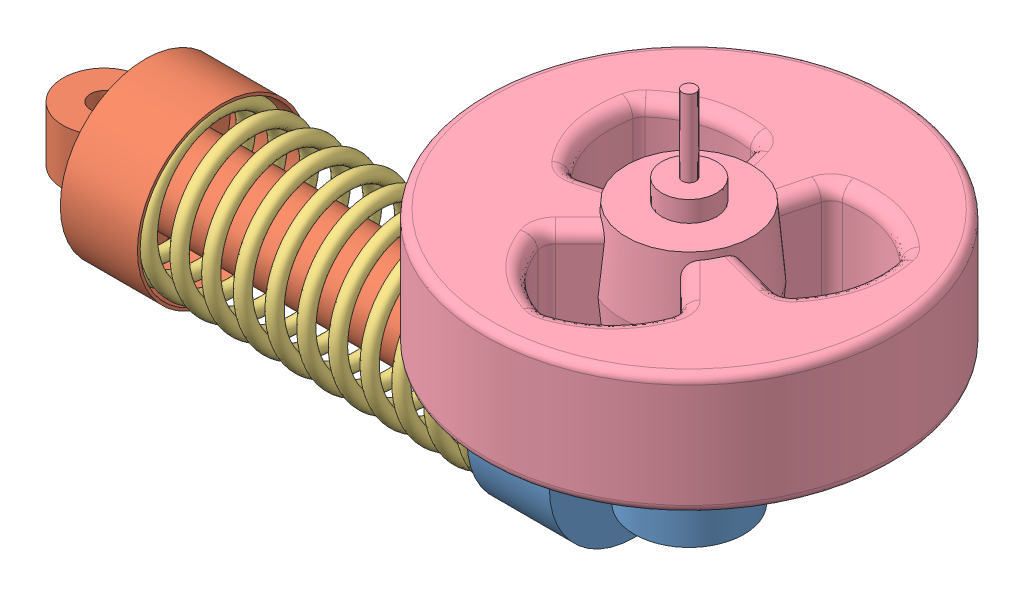
SolidWorks assembly suspension systim and tyre, configuration Default. Lengths in mm.
Overall size (330.09 152.31 203.38).
4 component instances, 4 part files, 8 mates.
Components (placement in the parent):
- part 1-1: part 1 [Default] at (125.6943 80.1946 134.3032) size (193.4 62 62)
- Part2-1: Part2 [Default] at (-52.7057 80.1946 134.3032) x (-1 0 0) z (0 0 1) size (187.4 62 62)
- Part6^suspension systim and tyre-1: Part6^suspension systim and tyre [Default] at (125.6943 80.1946 134.3032) size (178.4 63 63) (virtual)
- tyre-1: tyre [Default] at (145.6943 141.0026 134.3032) x (-0.497503 0 0.867462) z (0 -1 0) size (149 149 120)
Mates (geometry in assembly coordinates):
- Concentric1: concentric aligned: cylinder of part 1-1 through (125.6943 80.1946 134.3032) axis (1 0 0) radius 10; cylinder of Part2-1 through (-47.7057 80.1946 134.3032) axis (1 0 0) radius 15
- LimitDistance1: limit distance = 20 mm anti-aligned: plane of Part2-1 through (104.6943 65.1946 134.3032) normal (1 0 0); plane of part 1-1 through (124.6943 90.1946 134.3032) normal (-1 0 0)
- InPlace1: in place: plane of ? through (125.6943 80.1946 134.3032) normal (0 0 1); plane of ? through (125.6943 80.1946 134.3032) normal (0 0 1); moOrthogonalPlaneRef_w of ? through (125.6943 80.1946 134.3032) normal (0 0 1); plane of ? through (125.6943 80.1946 134.3032) normal (0 1 0); plane of ? through (125.6943 80.1946 134.3032) normal (0 0 1); plane of ? through (125.6943 80.1946 134.3032) normal (1 0 0); plane of ? through (125.6943 80.1946 134.3032) normal (0 0 1); unknown of ?
- Coincident1: coincident aligned: plane of ?; plane of ?
- Coincident2: coincident aligned: moOrthogonalPlaneRef_w of part 1-1 through (125.6943 80.1946 134.3032) axis (0 1 0); plane of Part6^Assem1-1 through (125.6943 80.1946 134.3032) normal (0 1 0)
- Coincident3: coincident anti-aligned: moOrthogonalPlaneRef_w of part 1-1 through (125.6943 80.1946 134.3032) axis (-1 0 0); plane of Part6^Assem1-1 through (125.6943 80.1946 134.3032) normal (1 0 0)
- Coincident4: coincident anti-aligned: plane of part 1-1 through (145.6943 90.1946 134.3032) normal (0 1 0); circle of Part2-1
- Concentric2: concentric aligned: circle of part 1-1; cylinder of tyre-1 through (145.6943 81.0026 134.3032) axis (0 1 0) radius 2.5
